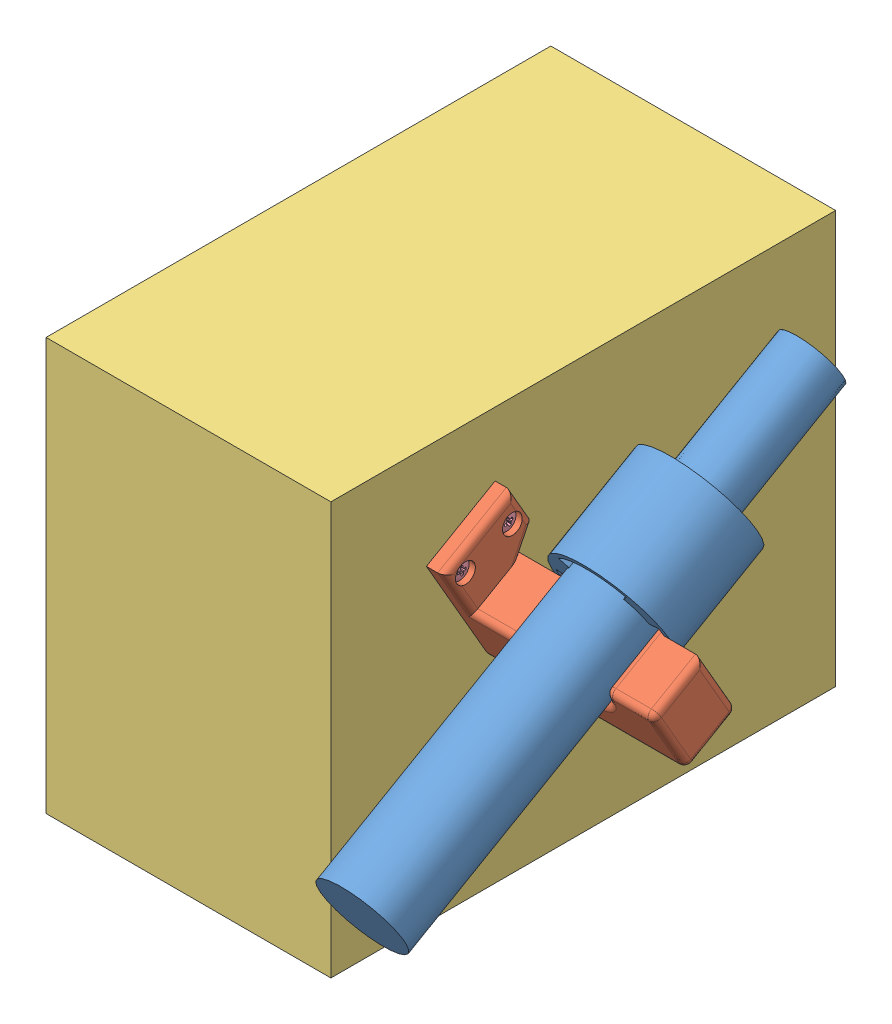
SolidWorks assembly Assem1, configuration Default. Lengths in mm.
Overall size (170.18 160.33 215).
8 component instances, 5 part files, 19 mates.
Components (placement in the parent):
- nozzle-1: nozzle [Default] at (-99.2685 226.2943 99.4899) x (1 0 0) z (0 -0.5 0.866025) size (40.64 40.64 182.88)
- holder-1: holder [Default] at (-1090.9378 -3067.9639 -1802.4509) x (1 0 0) z (0 -0.5 0.866025) size (69.85 45.72 33.25)
- unit-1: unit [Default] at (-187.5335 196.8375 -17.3573) size (100.33 145.26 177.8)
- 4-40_screw-1: 4-40_screw [94836A210] at (-140.5435 230.3782 119.3709) x (0 -0.998054 -0.06236) z (1 0 0) size (6.99 6.99 8.66)
- 4-40_screw-2: 4-40_screw [94836A210] at (-140.5435 237.0838 102.8609) x (0 0.923805 0.382863) z (1 0 0) size (6.99 6.99 8.66)
- magnet-1: magnet [Default] at (-79.0972 211.1286 102.4658) x (0.334116 0.129197 0.933635) z (-0.866025 0.433013 0.25) size (12.01 12.01 10.65)
- magnet-2: magnet [Default] at (-99.2685 201.043 96.6428) x (1 0 0) z (0 0.866025 0.5) size (12.01 12.01 10.65)
- magnet-3: magnet [Default] at (-119.4398 211.1286 102.4658) x (-0.470583 0.536903 0.700205) z (0.866025 0.433013 0.25) size (12.01 12.01 10.65)
Mates (geometry in assembly coordinates):
- Parallel1: parallel anti-aligned: plane of unit-1 through (-137.3685 124.2062 160.4427) normal (1 0 0); plane of holder-1 through (-137.3685 -3067.9639 -1802.4509) normal (-1 0 0)
- Concentric1: concentric aligned: cylinder of nozzle-1 through (-99.2685 175.4943 187.4781) axis (0 0.5 -0.866025) radius 14.6939; cylinder of holder-1 through (-99.2685 216.1343 117.0876) axis (0 0.5 -0.866025) radius 14.6939
- Coincident8: coincident anti-aligned: plane of nozzle-1 through (-99.2685 226.2943 99.4899) normal (0 -0.5 0.866025); plane of holder-1 through (-1090.9378 -3067.9639 -1802.4509) normal (0 0.5 -0.866025)
- Concentric3: concentric aligned: cylinder of holder-1 through (-137.3685 230.3782 119.3709) axis (1 0 0) radius 1.4859; cylinder of unit-1 through (-315.1685 230.3782 119.3709) axis (1 0 0) radius 1.4478
- Parallel2: parallel aligned: cylinder of holder-1 through (-137.3685 237.0838 102.8609) axis (1 0 0) radius 1.4859; cylinder of unit-1 through (-315.1685 237.0838 102.8609) axis (1 0 0) radius 1.4478
- Coincident13: coincident anti-aligned: plane of holder-1 through (-137.3685 -3067.9639 -1802.4509) normal (-1 0 0); plane of unit-1 through (-137.3685 124.2062 160.4427) normal (1 0 0)
- Concentric5: concentric aligned: cylinder of unit-1 through (-315.1685 230.3782 119.3709) axis (1 0 0) radius 1.4478; line of 4-40_screw-1 through (-140.5435 230.3782 119.3709) axis (1 0 0)
- Distance2: distance = 3.175 mm anti-aligned: plane of 4-40_screw-1 through (-134.1935 230.3782 119.3709) normal (-1 0 0); plane of unit-1 through (-137.3685 124.2062 160.4427) normal (1 0 0)
- Concentric6: concentric aligned: cylinder of unit-1 through (-315.1685 237.0838 102.8609) axis (1 0 0) radius 1.4478; line of 4-40_screw-2 through (-140.5435 237.0838 102.8609) axis (1 0 0)
- Distance3: distance = 3.175 mm anti-aligned: plane of 4-40_screw-2 through (-134.1935 237.0838 102.8609) normal (-1 0 0); plane of unit-1 through (-137.3685 124.2062 160.4427) normal (1 0 0)
- Perpendicular1: perpendicular: line of nozzle-1 through (-99.2685 226.2943 99.4899) axis (0 0.866025 0.5); plane of holder-1 through (-1090.9378 194.1372 104.3876) normal (0 -0.866025 -0.5)
- Angle2: planar angle = 0.523599 rad aligned: plane of unit-1 through (-237.6985 124.2062 160.4427) normal (0 -1 0); plane of holder-1 through (-1090.9378 194.1372 104.3876) normal (0 -0.866025 -0.5)
- Coincident38: coincident anti-aligned: line of holder-1 through (-99.2685 221.2143 108.2887) axis (0.866025 -0.433013 -0.25); line of magnet-1 through (-79.0972 211.1286 102.4658) axis (-0.866025 0.433013 0.25)
- Coincident39: coincident: point of holder-1; point of magnet-1
- Coincident40: coincident anti-aligned: line of holder-1 through (-99.2685 221.2143 108.2887) axis (0 -0.866025 -0.5); line of magnet-2 through (-99.2685 201.043 96.6428) axis (0 0.866025 0.5)
- Coincident41: coincident: point of holder-1; point of magnet-2
- Coincident42: coincident anti-aligned: line of holder-1 through (-99.2685 221.2143 108.2887) axis (-0.866025 -0.433013 -0.25); line of magnet-3 through (-119.4398 211.1286 102.4658) axis (0.866025 0.433013 0.25)
- Coincident43: coincident: point of holder-1; point of magnet-3
- Perpendicular3: perpendicular: plane of holder-1 through (-1090.9378 -3078.1239 -1784.8533) normal (0 -0.5 0.866025); line of magnet-2 through (-99.2685 203.6166 98.1287) axis (0 -0.5 0.866025)
